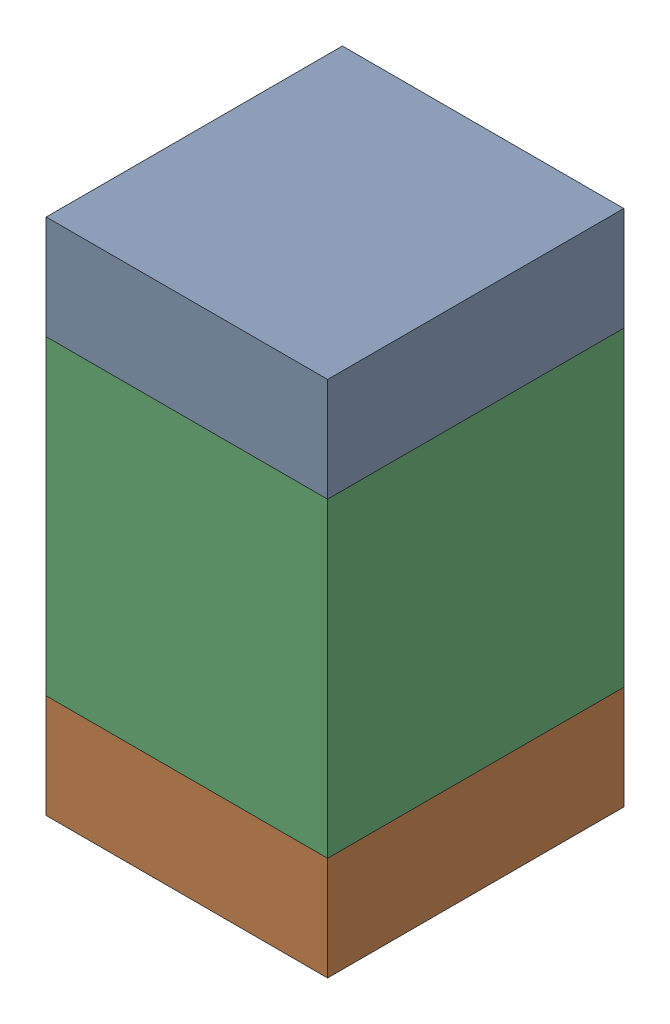
SolidWorks assembly C421PCB, configuration Default. Lengths in mm.
Overall size (0.95 1.75 1).
6 component instances, 2 part files, 0 mates.
Components (placement in the parent):
- 761616520-1: 761616520 [Default] at (88.3 86.4 -2.6638) size (0.95 0.35 1)
  - Extruded_6-1: Extruded_6 [Default] at origin size (0.95 0.35 1)
- 761616520-2: 761616520 [Default] at (88.3 85 -2.6638) size (0.95 0.35 1)
  - Extruded_6-1: Extruded_6 [Default] at origin size (0.95 0.35 1)
- 761616384-1: 761616384 [Default] at (88.3 85.7 -2.6638) size (0.95 1.05 1)
  - Extruded_5-1: Extruded_5 [Default] at origin size (0.95 1.05 1)
